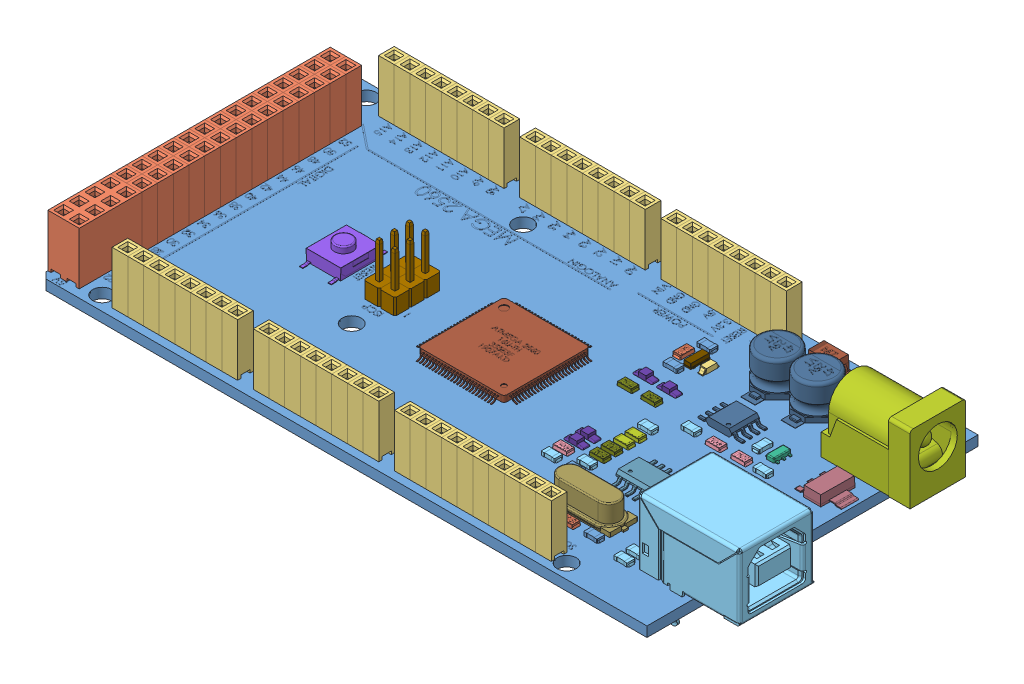
SolidWorks assembly Arduino Mega ATmega 2560, configuration Default. Lengths in mm.
Overall size (109.9 15.25 53.6).
199 component instances, 29 part files, 0 mates.
Components (placement in the parent):
- Arduino Mega PCB-1: Arduino Mega PCB [Default] at origin size (101.8 1.64 53.6)
- headerFemalex18x2-1: headerFemalex18x2 [Default] at (-44.415 1.63 17.88) x (0 0 -1) z (1 0 0) size (45.72 11.5 5.08)
- headerFemale-1: headerFemale [Default] at (-22.825 1.63 -24.23) size (2.54 11.5 2.54)
- headerFemale-2: headerFemale [Default] at (-25.365 1.63 -24.23) size (2.54 11.5 2.54)
- headerFemale-3: headerFemale [Default] at (2.815 1.63 24.23) size (2.54 11.5 2.54)
- headerFemale-4: headerFemale [Default] at (-25.125 1.63 24.23) size (2.54 11.5 2.54)
- headerFemale-5: headerFemale [Default] at (20.595 1.63 24.23) size (2.54 11.5 2.54)
- headerFemale-6: headerFemale [Default] at (-20.285 1.63 -24.23) size (2.54 11.5 2.54)
- headerFemale-7: headerFemale [Default] at (0.035 1.63 -24.23) size (2.54 11.5 2.54)
- headerFemale-8: headerFemale [Default] at (5.115 1.63 -24.23) size (2.54 11.5 2.54)
- headerFemale-9: headerFemale [Default] at (0.275 1.63 24.23) size (2.54 11.5 2.54)
- headerFemale-10: headerFemale [Default] at (-4.805 1.63 24.23) size (2.54 11.5 2.54)
- headerFemale-11: headerFemale [Default] at (-2.505 1.63 -24.23) size (2.54 11.5 2.54)
- headerFemale-12: headerFemale [Default] at (-22.585 1.63 24.23) size (2.54 11.5 2.54)
- headerFemale-13: headerFemale [Default] at (-2.265 1.63 24.23) size (2.54 11.5 2.54)
- headerFemale-14: headerFemale [Default] at (12.735 1.63 -24.23) size (2.54 11.5 2.54)
- headerFemale-15: headerFemale [Default] at (15.515 1.63 24.23) size (2.54 11.5 2.54)
- headerFemale-16: headerFemale [Default] at (22.895 1.63 -24.23) size (2.54 11.5 2.54)
- headerFemale-17: headerFemale [Default] at (10.195 1.63 -24.23) size (2.54 11.5 2.54)
- headerFemale-18: headerFemale [Default] at (-35.525 1.63 -24.23) size (2.54 11.5 2.54)
- headerFemale-19: headerFemale [Default] at (27.975 1.63 -24.23) size (2.54 11.5 2.54)
- headerFemale-20: headerFemale [Default] at (30.755 1.63 24.23) size (2.54 11.5 2.54)
- headerFemale-21: headerFemale [Default] at (-7.585 1.63 -24.23) size (2.54 11.5 2.54)
- headerFemale-22: headerFemale [Default] at (35.835 1.63 24.23) size (2.54 11.5 2.54)
- headerFemale-23: headerFemale [Default] at (18.055 1.63 24.23) size (2.54 11.5 2.54)
- headerFemale-24: headerFemale [Default] at (-12.425 1.63 24.23) size (2.54 11.5 2.54)
- headerFemale-25: headerFemale [Default] at (28.215 1.63 24.23) size (2.54 11.5 2.54)
- headerFemale-26: headerFemale [Default] at (-7.345 1.63 24.23) size (2.54 11.5 2.54)
- headerFemale-27: headerFemale [Default] at (17.815 1.63 -24.23) size (2.54 11.5 2.54)
- headerFemale-28: headerFemale [Default] at (23.135 1.63 24.23) size (2.54 11.5 2.54)
- headerFemale-29: headerFemale [Default] at (10.435 1.63 24.23) size (2.54 11.5 2.54)
- headerFemale-30: headerFemale [Default] at (-32.985 1.63 -24.23) size (2.54 11.5 2.54)
- headerFemale-31: headerFemale [Default] at (-10.125 1.63 -24.23) size (2.54 11.5 2.54)
- headerFemale-32: headerFemale [Default] at (-30.445 1.63 -24.23) size (2.54 11.5 2.54)
- headerFemale-33: headerFemale [Default] at (-17.745 1.63 -24.23) size (2.54 11.5 2.54)
- headerFemale-34: headerFemale [Default] at (-27.665 1.63 24.23) size (2.54 11.5 2.54)
- headerFemale-35: headerFemale [Default] at (5.355 1.63 24.23) size (2.54 11.5 2.54)
- headerFemale-36: headerFemale [Default] at (20.355 1.63 -24.23) size (2.54 11.5 2.54)
- headerFemale-37: headerFemale [Default] at (25.675 1.63 24.23) size (2.54 11.5 2.54)
- headerFemale-38: headerFemale [Default] at (-17.505 1.63 24.23) size (2.54 11.5 2.54)
- headerFemale-39: headerFemale [Default] at (-27.905 1.63 -24.23) size (2.54 11.5 2.54)
- headerFemale-40: headerFemale [Default] at (-14.965 1.63 24.23) size (2.54 11.5 2.54)
- headerFemale-41: headerFemale [Default] at (2.575 1.63 -24.23) size (2.54 11.5 2.54)
- headerFemale-42: headerFemale [Default] at (33.295 1.63 24.23) size (2.54 11.5 2.54)
- headerFemale-43: headerFemale [Default] at (25.435 1.63 -24.23) size (2.54 11.5 2.54)
- headerFemale-44: headerFemale [Default] at (-20.045 1.63 24.23) size (2.54 11.5 2.54)
- headerFemale-45: headerFemale [Default] at (-12.665 1.63 -24.23) size (2.54 11.5 2.54)
- headerFemale-46: headerFemale [Default] at (15.275 1.63 -24.23) size (2.54 11.5 2.54)
- headerFemale-47: headerFemale [Default] at (-30.205 1.63 24.23) size (2.54 11.5 2.54)
- headerFemale-48: headerFemale [Default] at (38.375 1.63 24.23) size (2.54 11.5 2.54)
- headerFemale-49: headerFemale [Default] at (-5.045 1.63 -24.23) size (2.54 11.5 2.54)
- headerFemale-50: headerFemale [Default] at (7.895 1.63 24.23) size (2.54 11.5 2.54)
- solder-1: solder [Default] at (29.4996 0 24.2186) x (-0.837169 0 -0.546944) z (-0.546944 0 0.837169) size (1.17 0.65 1.17)
- solder-2: solder [Default] at (24.4196 0 24.2186) x (-0.837169 0 -0.546944) z (-0.546944 0 0.837169) size (1.17 0.65 1.17)
- solder-3: solder [Default] at (-46.9277 0 -11.3414) x (-0.837169 0 -0.546944) z (-0.546944 0 0.837169) size (1.17 0.65 1.17)
- solder-4: solder [Default] at (-46.9277 0 16.5986) x (-0.837169 0 -0.546944) z (-0.546944 0 0.837169) size (1.17 0.65 1.17)
- solder-5: solder [Default] at (-13.6804 0 24.2186) x (-0.837169 0 -0.546944) z (-0.546944 0 0.837169) size (1.17 0.65 1.17)
- solder-6: solder [Default] at (-44.3877 0 1.3586) x (-0.837169 0 -0.546944) z (-0.546944 0 0.837169) size (1.17 0.65 1.17)
- solder-7: solder [Default] at (-34.2509 0 -24.251) x (-0.837169 0 -0.546944) z (-0.546944 0 0.837169) size (1.17 0.65 1.17)
- solder-8: solder [Default] at (16.7996 0 24.2186) x (-0.837169 0 -0.546944) z (-0.546944 0 0.837169) size (1.17 0.65 1.17)
- solder-9: solder [Default] at (-46.9277 0 -3.7214) x (-0.837169 0 -0.546944) z (-0.546944 0 0.837169) size (1.17 0.65 1.17)
- solder-10: solder [Default] at (-31.7109 0 -24.251) x (-0.837169 0 -0.546944) z (-0.546944 0 0.837169) size (1.17 0.65 1.17)
- solder-11: solder [Default] at (9.1796 0 24.2186) x (-0.837169 0 -0.546944) z (-0.546944 0 0.837169) size (1.17 0.65 1.17)
- solder-12: solder [Default] at (-39.3309 0 -24.251) x (-0.837169 0 -0.546944) z (-0.546944 0 0.837169) size (1.17 0.65 1.17)
- solder-13: solder [Default] at (-44.3877 0 -16.4214) x (-0.837169 0 -0.546944) z (-0.546944 0 0.837169) size (1.17 0.65 1.17)
- solder-14: solder [Default] at (14.0091 0 -24.251) x (-0.837169 0 -0.546944) z (-0.546944 0 0.837169) size (1.17 0.65 1.17)
- solder-15: solder [Default] at (11.4691 0 -24.251) x (-0.837169 0 -0.546944) z (-0.546944 0 0.837169) size (1.17 0.65 1.17)
- solder-16: solder [Default] at (-46.9277 0 -13.8814) x (-0.837169 0 -0.546944) z (-0.546944 0 0.837169) size (1.17 0.65 1.17)
- solder-17: solder [Default] at (3.8491 0 -24.251) x (-0.837169 0 -0.546944) z (-0.546944 0 0.837169) size (1.17 0.65 1.17)
- solder-18: solder [Default] at (8.9291 0 -24.251) x (-0.837169 0 -0.546944) z (-0.546944 0 0.837169) size (1.17 0.65 1.17)
- solder-19: solder [Default] at (-46.9277 0 6.4386) x (-0.837169 0 -0.546944) z (-0.546944 0 0.837169) size (1.17 0.65 1.17)
- solder-20: solder [Default] at (-3.7709 0 -24.251) x (-0.837169 0 -0.546944) z (-0.546944 0 0.837169) size (1.17 0.65 1.17)
- solder-21: solder [Default] at (-46.9277 0 -18.9614) x (-0.837169 0 -0.546944) z (-0.546944 0 0.837169) size (1.17 0.65 1.17)
- solder-22: solder [Default] at (-13.9309 0 -24.251) x (-0.837169 0 -0.546944) z (-0.546944 0 0.837169) size (1.17 0.65 1.17)
- solder-23: solder [Default] at (-11.3909 0 -24.251) x (-0.837169 0 -0.546944) z (-0.546944 0 0.837169) size (1.17 0.65 1.17)
- solder-24: solder [Default] at (-44.3877 0 24.2186) x (-0.837169 0 -0.546944) z (-0.546944 0 0.837169) size (1.17 0.65 1.17)
- solder-25: solder [Default] at (-44.3877 0 -18.9614) x (-0.837169 0 -0.546944) z (-0.546944 0 0.837169) size (1.17 0.65 1.17)
- solder-26: solder [Default] at (-8.8509 0 -24.251) x (-0.837169 0 -0.546944) z (-0.546944 0 0.837169) size (1.17 0.65 1.17)
- solder-27: solder [Default] at (45.1853 0 12.6794) x (-0.837169 0 -0.546944) z (-0.546944 0 0.837169) size (1.17 0.65 1.17)
- solder-28: solder [Default] at (-23.8404 0 24.2186) x (-0.837169 0 -0.546944) z (-0.546944 0 0.837169) size (1.17 0.65 1.17)
- solder-29: solder [Default] at (-44.3877 0 16.5986) x (-0.837169 0 -0.546944) z (-0.546944 0 0.837169) size (1.17 0.65 1.17)
- solder-30: solder [Default] at (19.0891 0 -24.251) x (-0.837169 0 -0.546944) z (-0.546944 0 0.837169) size (1.17 0.65 1.17)
- solder-31: solder [Default] at (-34.0004 0 24.2186) x (-0.837169 0 -0.546944) z (-0.546944 0 0.837169) size (1.17 0.65 1.17)
- solder-32: solder [Default] at (-3.5204 0 24.2186) x (-0.837169 0 -0.546944) z (-0.546944 0 0.837169) size (1.17 0.65 1.17)
- solder-33: solder [Default] at (-46.9277 0 3.8986) x (-0.837169 0 -0.546944) z (-0.546944 0 0.837169) size (1.17 0.65 1.17)
- solder-34: solder [Default] at (1.5596 0 24.2186) x (-0.837169 0 -0.546944) z (-0.546944 0 0.837169) size (1.17 0.65 1.17)
- solder-35: solder [Default] at (19.3396 0 24.2186) x (-0.837169 0 -0.546944) z (-0.546944 0 0.837169) size (1.17 0.65 1.17)
- solder-36: solder [Default] at (-18.7604 0 24.2186) x (-0.837169 0 -0.546944) z (-0.546944 0 0.837169) size (1.17 0.65 1.17)
- solder-37: solder [Default] at (-44.3877 0 -8.8014) x (-0.837169 0 -0.546944) z (-0.546944 0 0.837169) size (1.17 0.65 1.17)
- solder-38: solder [Default] at (16.5491 0 -24.251) x (-0.837169 0 -0.546944) z (-0.546944 0 0.837169) size (1.17 0.65 1.17)
- solder-39: solder [Default] at (45.1853 0 15.1294) x (-0.837169 0 -0.546944) z (-0.546944 0 0.837169) size (1.17 0.65 1.17)
- solder-40: solder [Default] at (-46.9277 0 19.1386) x (-0.837169 0 -0.546944) z (-0.546944 0 0.837169) size (1.17 0.65 1.17)
- solder-41: solder [Default] at (-31.4604 0 24.2186) x (-0.837169 0 -0.546944) z (-0.546944 0 0.837169) size (1.17 0.65 1.17)
- solder-42: solder [Default] at (21.8796 0 24.2186) x (-0.837169 0 -0.546944) z (-0.546944 0 0.837169) size (1.17 0.65 1.17)
- solder-43: solder [Default] at (-46.9277 0 -1.1814) x (-0.837169 0 -0.546944) z (-0.546944 0 0.837169) size (1.17 0.65 1.17)
- solder-44: solder [Default] at (-11.1404 0 24.2186) x (-0.837169 0 -0.546944) z (-0.546944 0 0.837169) size (1.17 0.65 1.17)
- solder-45: solder [Default] at (-21.3004 0 24.2186) x (-0.837169 0 -0.546944) z (-0.546944 0 0.837169) size (1.17 0.65 1.17)
- solder-46: solder [Default] at (-36.5404 0 24.2186) x (-0.837169 0 -0.546944) z (-0.546944 0 0.837169) size (1.17 0.65 1.17)
- solder-47: solder [Default] at (-24.0909 0 -24.251) x (-0.837169 0 -0.546944) z (-0.546944 0 0.837169) size (1.17 0.65 1.17)
- solder-48: solder [Default] at (-36.7909 0 -24.251) x (-0.837169 0 -0.546944) z (-0.546944 0 0.837169) size (1.17 0.65 1.17)
- solder-49: solder [Default] at (-44.3877 0 19.1386) x (-0.837169 0 -0.546944) z (-0.546944 0 0.837169) size (1.17 0.65 1.17)
- solder-50: solder [Default] at (-46.9277 0 14.0586) x (-0.837169 0 -0.546944) z (-0.546944 0 0.837169) size (1.17 0.65 1.17)
- solder-51: solder [Default] at (32.0396 0 24.2186) x (-0.837169 0 -0.546944) z (-0.546944 0 0.837169) size (1.17 0.65 1.17)
- solder-52: solder [Default] at (-44.3877 0 -11.3414) x (-0.837169 0 -0.546944) z (-0.546944 0 0.837169) size (1.17 0.65 1.17)
- solder-53: solder [Default] at (-0.9804 0 24.2186) x (-0.837169 0 -0.546944) z (-0.546944 0 0.837169) size (1.17 0.65 1.17)
- solder-54: solder [Default] at (-44.3877 0 11.5186) x (-0.837169 0 -0.546944) z (-0.546944 0 0.837169) size (1.17 0.65 1.17)
- solder-55: solder [Default] at (-44.3877 0 8.9786) x (-0.837169 0 -0.546944) z (-0.546944 0 0.837169) size (1.17 0.65 1.17)
- solder-56: solder [Default] at (-28.9204 0 24.2186) x (-0.837169 0 -0.546944) z (-0.546944 0 0.837169) size (1.17 0.65 1.17)
- solder-57: solder [Default] at (-41.8709 0 -24.251) x (-0.837169 0 -0.546944) z (-0.546944 0 0.837169) size (1.17 0.65 1.17)
- solder-58: solder [Default] at (-46.9277 0 -16.4214) x (-0.837169 0 -0.546944) z (-0.546944 0 0.837169) size (1.17 0.65 1.17)
- solder-59: solder [Default] at (21.6291 0 -24.251) x (-0.837169 0 -0.546944) z (-0.546944 0 0.837169) size (1.17 0.65 1.17)
- solder-60: solder [Default] at (-26.6309 0 -24.251) x (-0.837169 0 -0.546944) z (-0.546944 0 0.837169) size (1.17 0.65 1.17)
- solder-61: solder [Default] at (-46.9277 0 8.9786) x (-0.837169 0 -0.546944) z (-0.546944 0 0.837169) size (1.17 0.65 1.17)
- solder-62: solder [Default] at (-8.6004 0 24.2186) x (-0.837169 0 -0.546944) z (-0.546944 0 0.837169) size (1.17 0.65 1.17)
- solder-63: solder [Default] at (-44.3877 0 6.4386) x (-0.837169 0 -0.546944) z (-0.546944 0 0.837169) size (1.17 0.65 1.17)
- solder-64: solder [Default] at (-46.9277 0 -8.8014) x (-0.837169 0 -0.546944) z (-0.546944 0 0.837169) size (1.17 0.65 1.17)
- solder-65: solder [Default] at (6.3891 0 -24.251) x (-0.837169 0 -0.546944) z (-0.546944 0 0.837169) size (1.17 0.65 1.17)
- solder-66: solder [Default] at (-6.3109 0 -24.251) x (-0.837169 0 -0.546944) z (-0.546944 0 0.837169) size (1.17 0.65 1.17)
- solder-67: solder [Default] at (-44.3877 0 -13.8814) x (-0.837169 0 -0.546944) z (-0.546944 0 0.837169) size (1.17 0.65 1.17)
- solder-68: solder [Default] at (-6.0604 0 24.2186) x (-0.837169 0 -0.546944) z (-0.546944 0 0.837169) size (1.17 0.65 1.17)
- solder-69: solder [Default] at (-44.3877 0 -1.1814) x (-0.837169 0 -0.546944) z (-0.546944 0 0.837169) size (1.17 0.65 1.17)
- solder-70: solder [Default] at (-26.3804 0 24.2186) x (-0.837169 0 -0.546944) z (-0.546944 0 0.837169) size (1.17 0.65 1.17)
- solder-71: solder [Default] at (43.2353 0 15.1294) x (-0.837169 0 -0.546944) z (-0.546944 0 0.837169) size (1.17 0.65 1.17)
- solder-72: solder [Default] at (-44.3877 0 14.0586) x (-0.837169 0 -0.546944) z (-0.546944 0 0.837169) size (1.17 0.65 1.17)
- solder-73: solder [Default] at (43.2353 0 12.6794) x (-0.837169 0 -0.546944) z (-0.546944 0 0.837169) size (1.17 0.65 1.17)
- solder-74: solder [Default] at (-46.9277 0 24.2186) x (-0.837169 0 -0.546944) z (-0.546944 0 0.837169) size (1.17 0.65 1.17)
- solder-75: solder [Default] at (-29.1709 0 -24.251) x (-0.837169 0 -0.546944) z (-0.546944 0 0.837169) size (1.17 0.65 1.17)
- solder-76: solder [Default] at (-44.3877 0 -3.7214) x (-0.837169 0 -0.546944) z (-0.546944 0 0.837169) size (1.17 0.65 1.17)
- solder-77: solder [Default] at (-46.9277 0 21.6786) x (-0.837169 0 -0.546944) z (-0.546944 0 0.837169) size (1.17 0.65 1.17)
- solder-78: solder [Default] at (-46.9277 0 1.3586) x (-0.837169 0 -0.546944) z (-0.546944 0 0.837169) size (1.17 0.65 1.17)
- solder-79: solder [Default] at (26.9596 0 24.2186) x (-0.837169 0 -0.546944) z (-0.546944 0 0.837169) size (1.17 0.65 1.17)
- solder-80: solder [Default] at (-44.3877 0 21.6786) x (-0.837169 0 -0.546944) z (-0.546944 0 0.837169) size (1.17 0.65 1.17)
- solder-81: solder [Default] at (4.0996 0 24.2186) x (-0.837169 0 -0.546944) z (-0.546944 0 0.837169) size (1.17 0.65 1.17)
- solder-82: solder [Default] at (-46.9277 0 -6.2614) x (-0.837169 0 -0.546944) z (-0.546944 0 0.837169) size (1.17 0.65 1.17)
- solder-83: solder [Default] at (-44.3877 0 3.8986) x (-0.837169 0 -0.546944) z (-0.546944 0 0.837169) size (1.17 0.65 1.17)
- solder-84: solder [Default] at (-16.4709 0 -24.251) x (-0.837169 0 -0.546944) z (-0.546944 0 0.837169) size (1.17 0.65 1.17)
- solder-85: solder [Default] at (14.2596 0 24.2186) x (-0.837169 0 -0.546944) z (-0.546944 0 0.837169) size (1.17 0.65 1.17)
- solder-86: solder [Default] at (11.7196 0 24.2186) x (-0.837169 0 -0.546944) z (-0.546944 0 0.837169) size (1.17 0.65 1.17)
- solder-87: solder [Default] at (-46.9277 0 11.5186) x (-0.837169 0 -0.546944) z (-0.546944 0 0.837169) size (1.17 0.65 1.17)
- solder-88: solder [Default] at (-44.3877 0 -6.2614) x (-0.837169 0 -0.546944) z (-0.546944 0 0.837169) size (1.17 0.65 1.17)
- solder-89: solder [Default] at (-1.2309 0 -24.251) x (-0.837169 0 -0.546944) z (-0.546944 0 0.837169) size (1.17 0.65 1.17)
- solder-90: solder [Default] at (-19.0109 0 -24.251) x (-0.837169 0 -0.546944) z (-0.546944 0 0.837169) size (1.17 0.65 1.17)
- USBInput-1: USBInput [Default] at (51.825 1.63 -24.14) x (0 0 1) z (-1 0 0) size (13.72 15.2 16.5)
- solder1.8-1: solder1.8 [Default] at (47.8972 0 19.9763) x (-0.837169 0 -0.546944) z (-0.546944 0 0.837169) size (1.8 0.65 1.8)
- solder1.8-2: solder1.8 [Default] at (47.8972 0 7.7416) x (-0.837169 0 -0.546944) z (-0.546944 0 0.837169) size (1.8 0.65 1.8)
- PowerPlug-1: PowerPlug [Default] at (53.07 1.63 -23.075) x (0 0 1) z (-1 0 0) size (11.2 15.2 15.9)
- smdPushButton-1: smdPushButton [Default] at (-25.845 1.63 0) x (0 0 -1) z (1 0 0) size (9.1 2.85 5.6)
- headerMale-1: headerMale [Default] at (-17.525 1.63 2.54) size (2.54 11.1 2.54)
- headerMale-2: headerMale [Default] at (-14.985 1.63 -2.36) size (2.54 11.1 2.54)
- headerMale-3: headerMale [Default] at (-17.525 1.63 -2.36) size (2.54 11.1 2.54)
- headerMale-4: headerMale [Default] at (-14.985 1.63 0.09) size (2.54 11.1 2.54)
- headerMale-5: headerMale [Default] at (-17.525 1.63 0.09) size (2.54 11.1 2.54)
- headerMale-6: headerMale [Default] at (-14.985 1.63 2.54) size (2.54 11.1 2.54)
- smd47-1: smd47 [Default] at (33.2359 2.48 -17.65) x (0 0 1) z (-1 0 0) size (9.5 5.61 6.5)
- smd47-2: smd47 [Default] at (26.7359 2.48 -17.65) x (0 0 1) z (-1 0 0) size (9.5 5.61 6.5)
- smdM7diode-1: smdM7diode [Default] at (28.3956 1.68 -24.2569) size (6.5 2.13 2.5)
- smdCrystalOscillator-1: smdCrystalOscillator [Default] at (29.1027 1.83 15.1887) size (11.93 3.7 4.5)
- VoltageRegulatorAMS1112-1: VoltageRegulatorAMS1112 [Default] at (46.1008 1.63 -6.698) x (-0.008727 0 0.999962) z (-0.999962 0 -0.008727) size (5.5 1.65 6.7)
- smdChip16pin-1: smdChip16pin [Default] at (36.9716 2.355 6.6448) x (0 0 1) z (-1 0 0) size (7.3 1.22 10)
- tinyVoltageRegulator-1: tinyVoltageRegulator [Default] at (44.8587 1.63 1.7682) x (-0.008727 0 0.999962) z (-0.999962 0 -0.008727) size (2.75 0.7 2.1)
- smdResistor102-1: smdResistor102 [Default] at (18.9101 1.63 -5.1619) size (2.54 0.62 1.34)
- smdResistor102-2: smdResistor102 [Default] at (22.6192 1.63 5.022) size (2.54 0.62 1.34)
- smdResistor102-3: smdResistor102 [Default] at (22.6192 1.63 6.9092) size (2.54 0.62 1.34)
- smdResistor102-4: smdResistor102 [Default] at (15.0665 1.63 -5.1619) size (2.54 0.62 1.34)
- smdLED-1: smdLED [Default] at (18.6733 1.68 4.9107) size (3.2 0.84 1.28)
- smdLED-2: smdLED [Default] at (18.924 1.68 -8.0155) size (3.2 0.84 1.28)
- smdLED-3: smdLED [Default] at (18.6733 1.68 6.7615) size (3.2 0.84 1.28)
- smdLED-4: smdLED [Default] at (15.1024 1.68 -8.0155) size (3.2 0.84 1.28)
- tinyCrystal-1: tinyCrystal [Default] at (17.0851 1.63 -14.2329) x (-0.008727 0 0.999962) z (-0.999962 0 -0.008727) size (3.1 0.8 1.45)
- smdceramiccapacitorwhite-1: smdceramiccapacitorwhite [Default] at (22.5361 1.63 10.8878) size (2.55 0.62 1.3)
- smdceramiccapacitorwhite-2: smdceramiccapacitorwhite [Default] at (25.6965 1.63 18.6432) size (2.55 0.62 1.3)
- smdceramiccapacitorwhite-3: smdceramiccapacitorwhite [Default] at (33.3846 1.63 18.6432) size (2.55 0.62 1.3)
- smdceramiccapacitorwhite-4: smdceramiccapacitorwhite [Default] at (15.9897 1.63 -17.0687) size (2.55 0.62 1.3)
- smdceramiccapacitorwhite-5: smdceramiccapacitorwhite [Default] at (15.9897 1.63 -11.5964) size (2.55 0.62 1.3)
- smdResistor105-1: smdResistor105 [Default] at (14.9012 1.63 -14.3439) x (0.008727 0 -0.999962) z (0.999962 0 0.008727) size (2.54 0.62 1.34)
- smdResistor105-2: smdResistor105 [Default] at (29.3693 1.63 18.6473) size (2.54 0.62 1.34)
- tinyDiode-1: tinyDiode [Default] at (19.1387 1.64 -14.1257) x (0.008727 0 -0.999962) z (0.999962 0 0.008727) size (2.77 0.81 1)
- smdResistor103-1: smdResistor103 [Default] at (34.5333 1.63 -4.0924) size (2.54 0.62 1.34)
- smdResistor103-2: smdResistor103 [Default] at (18.6293 1.63 8.8506) size (2.54 0.62 1.34)
- smdResistor103-3: smdResistor103 [Default] at (30.4879 1.63 -4.0203) size (2.54 0.62 1.34)
- smdceramiccapacitor-1: smdceramiccapacitor [Default] at (22.5508 1.63 -0.8918) size (2.55 0.62 1.3)
- smdceramiccapacitor-2: smdceramiccapacitor [Default] at (22.5508 1.63 8.9496) size (2.55 0.62 1.3)
- smdceramiccapacitor-3: smdceramiccapacitor [Default] at (39.1596 1.63 7.9308) size (2.55 0.62 1.3)
- smdceramiccapacitor-4: smdceramiccapacitor [Default] at (39.1596 1.63 17.5628) size (2.55 0.62 1.3)
- smdceramiccapacitor-5: smdceramiccapacitor [Default] at (39.1596 1.63 19.5386) size (2.55 0.62 1.3)
- smdceramiccapacitor-6: smdceramiccapacitor [Default] at (18.6684 1.63 10.7899) size (2.55 0.62 1.3)
- smdceramiccapacitor-7: smdceramiccapacitor [Default] at (34.4647 1.63 -7.4993) x (0.008727 0 -0.999962) z (0.999962 0 0.008727) size (2.55 0.62 1.3)
- smdceramiccapacitor-8: smdceramiccapacitor [Default] at (38.0044 1.63 -4.0975) size (2.55 0.62 1.3)
- smdceramiccapacitor-9: smdceramiccapacitor [Default] at (26.4038 1.7166 -4.0641) size (2.55 0.62 1.3)
- tinyVoltageRegulator5pins-1: tinyVoltageRegulator5pins [Default] at (36.9485 1.63 -7.6363) x (-0.008727 0 0.999962) z (-0.999962 0 -0.008727) size (2.75 0.7 2.1)
- smdResistorNoNumber-1: smdResistorNoNumber [Default] at (22.6869 1.63 3.0647) size (2.54 0.61 1.34)
- smdResistorNoNumber-2: smdResistorNoNumber [Default] at (39.1794 1.63 11.6814) size (2.54 0.61 1.34)
- smdResistorNoNumber-3: smdResistorNoNumber [Default] at (39.1794 1.63 13.8493) size (2.54 0.61 1.34)
- smdResistorNoNumber-4: smdResistorNoNumber [Default] at (22.6869 1.63 1.2353) size (2.54 0.61 1.34)
- 1.7mmSmdCeramicCapacitorgray-1: 1.7mmSmdCeramicCapacitorgray [Default] at (39.277 1.5726 9.803) size (2.04 0.5 1.04)
- 1.7mmSmdCeramicCapacitorgray-2: 1.7mmSmdCeramicCapacitorgray [Default] at (39.277 1.5726 15.6439) size (2.04 0.5 1.04)
- CrystalNo5-1: CrystalNo5 [Default] at (48.5405 1.68 1.8508) x (0.008727 0 -0.999962) z (0.999962 0 0.008727) size (2.54 0.66 1.44)
- smdChip8pin-1: smdChip8pin [Default] at (28.6276 2.355 -10.7802) size (7.3 1.22 4.5)
- ATmega 2560-1: ATmega 2560 [Default] at (0.3651 1.63 0.2251) size (16.31 1.01 16.31)
